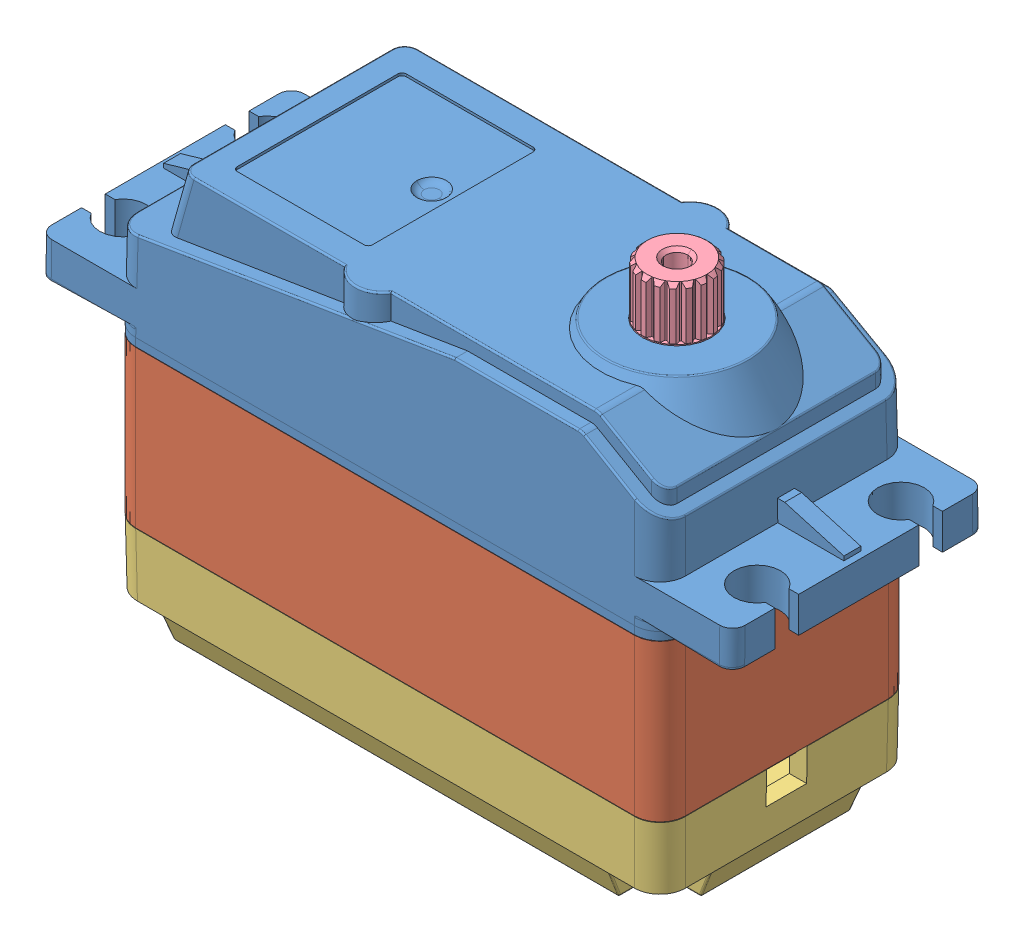
SolidWorks assembly asm-DS5160, configuration 默认. Lengths in mm.
Overall size (82.05 55.2 30.02).
5 component instances, 4 part files, 0 mates.
Components (placement in the parent):
- asm-DS5160.stp-1: asm-DS5160.stp [默认] at origin size (82.05 55.2 30.02)
  - SG-YOUYI.stp-1: SG-YOUYI.stp [默认] at origin size (82.05 19.95 30.02)
  - ZK-LV-YOUYI.stp-1: ZK-LV-YOUYI.stp [默认] at origin size (65 19.9 30)
  - DG-YOUYI.stp-1: DG-YOUYI.stp [默认] at origin size (65.02 10.46 30.02)
  - GE.stp-1: GE.stp [默认] at (19.5 -1.45 0) x (1 0 0) z (0 -1 0) size (21.9 21.88 25.15)
